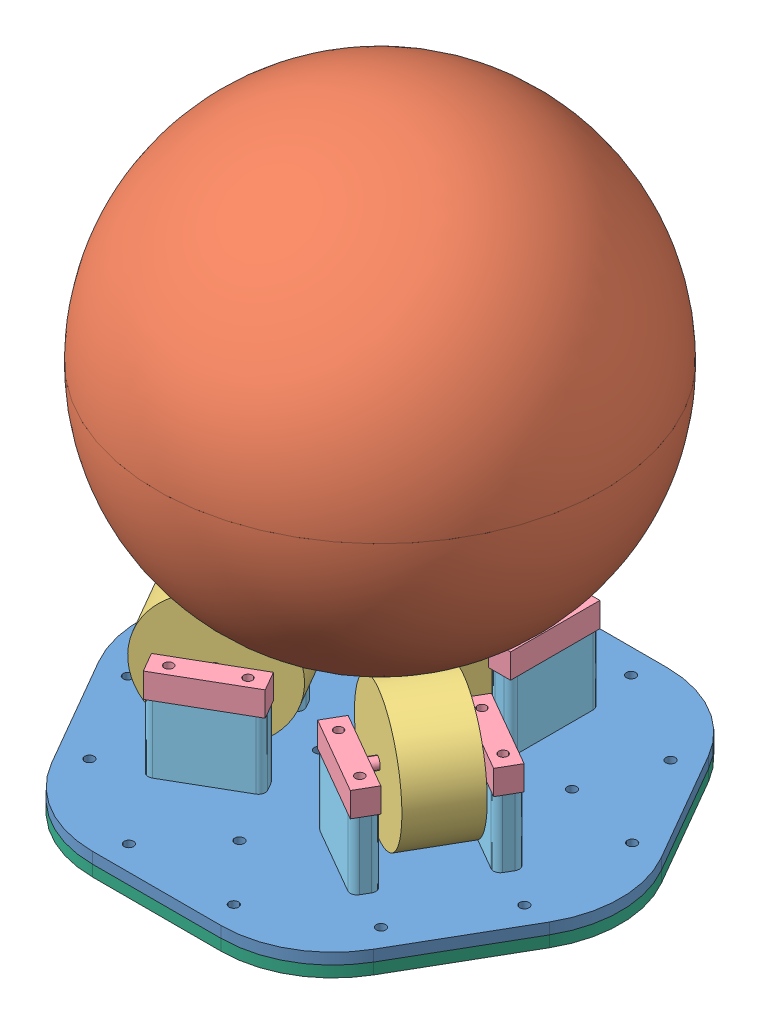
SolidWorks assembly 装配体-底座, configuration 默认. Lengths in mm.
Overall size (280.94 264.42 286.6).
19 component instances, 6 part files, 18 mates.
Components (placement in the parent):
- 底盘-上层-1: 底盘-上层 [默认] at (-27.1025 -44.7578 215.4701) size (215.47 5 200)
- 半球壳-直径200-1: 半球壳-直径200 [默认] at (-27.1025 114.6582 215.4701) x (0.999231 0 -0.039211) z (0.039211 0 0.999231) size (200 100 200)
- 装配体-支撑腿-1: 装配体-支撑腿 [默认] at (-21.0773 -11.8387 210.7731) x (0.072827 0.996458 -0.042047) z (-0.862958 0.084094 0.498229) size (66.06 57 58)
  - 全向轮-1: 全向轮 [默认] at (2.7132 -15.0551 58) size (58 28 58)
  - 全向轮固定架-1: 全向轮固定架 [默认] at (-12.0465 27.4449 36.6833) x (0 -1 0) z (-0.084094 0 0.996458) size (57 11 40)
  - 万向轮支撑腿-分体式-1: 万向轮支撑腿-分体式 [默认] at (-30.9792 17.4449 35.0855) x (0 -1 0) z (-0.084094 0 0.996458) size (10 30 40)
  - 万向轮支撑腿-分体式-2: 万向轮支撑腿-分体式 [默认] at (-30.9792 -29.5551 35.0855) x (0 -1 0) z (-0.084094 0 0.996458) size (10 30 40)
- 装配体-支撑腿-2: 装配体-支撑腿 [默认] at (-34.1827 -11.8387 212.6006) x (-0.072827 0.996458 -0.042047) z (0.862958 0.084094 0.498229) size (66.06 57 58)
  - 全向轮-1: 全向轮 [默认] at (2.7132 -15.0551 58) size (58 28 58)
  - 全向轮固定架-1: 全向轮固定架 [默认] at (-12.0465 27.4449 36.6833) x (0 -1 0) z (-0.084094 0 0.996458) size (57 11 40)
  - 万向轮支撑腿-分体式-1: 万向轮支撑腿-分体式 [默认] at (-30.9792 17.4449 35.0855) x (0 -1 0) z (-0.084094 0 0.996458) size (10 30 40)
  - 万向轮支撑腿-分体式-2: 万向轮支撑腿-分体式 [默认] at (-30.9792 -29.5551 35.0855) x (0 -1 0) z (-0.084094 0 0.996458) size (10 30 40)
- 装配体-支撑腿-3: 装配体-支撑腿 [默认] at (-28.1576 -11.8387 107.9037) x (0 0.996458 -0.084094) z (0 0.084094 0.996458) size (66.06 57 58)
  - 全向轮-1: 全向轮 [默认] at (2.7132 -15.0551 58) size (58 28 58)
  - 全向轮固定架-1: 全向轮固定架 [默认] at (-12.0465 27.4449 36.6833) x (0 -1 0) z (-0.084094 0 0.996458) size (57 11 40)
  - 万向轮支撑腿-分体式-1: 万向轮支撑腿-分体式 [默认] at (-30.9792 17.4449 35.0855) x (0 -1 0) z (-0.084094 0 0.996458) size (10 30 40)
  - 万向轮支撑腿-分体式-2: 万向轮支撑腿-分体式 [默认] at (-30.9792 -29.5551 35.0855) x (0 -1 0) z (-0.084094 0 0.996458) size (10 30 40)
- 底盘-下层-1: 底盘-下层 [默认] at (-27.1025 -49.7578 215.4701) x (-0.5 0 -0.866025) z (0.866025 0 -0.5) size (215.47 5 200)
- 半球壳-直径200-2: 半球壳-直径200 [默认] at (-27.1025 114.6582 215.4701) x (-0.999417 0 0.034133) z (0.034133 0 0.999417) size (200 100 200)
Mates (geometry in assembly coordinates):
- 平行1: parallel aligned: plane of 底盘-1 through (-27.1025 -39.7578 215.4701) normal (0 1 0); plane of 半球壳-直径200-1 through (-27.1025 114.6582 215.4701) normal (0 1 0)
- 重合1: coincident anti-aligned: plane of 底盘-上层-1 through (-27.1025 -39.7578 215.4701) normal (0 1 0); plane of 装配体-支撑腿-1/万向轮支撑腿-分体式-2 through (-38.8332 -39.7578 255.1518) normal (0 -1 0)
- 重合2: coincident anti-aligned: plane of 底盘-上层-1 through (-27.1025 -39.7578 215.4701) normal (0 1 0); plane of 装配体-支撑腿-2/万向轮支撑腿-分体式-1 through (-10.3717 -39.7578 246.4915) normal (0 -1 0)
- 重合3: coincident anti-aligned: plane of 底盘-上层-1 through (-27.1025 -39.7578 215.4701) normal (0 1 0); plane of 装配体-支撑腿-3/万向轮支撑腿-分体式-2 through (1.3975 -39.7578 145.4701) normal (0 -1 0)
- 同心4: concentric anti-aligned: cylinder of 底盘-上层-1 through (-50.6025 -44.7578 152.4701) axis (0 1 0) radius 2.1; cylinder of 装配体-支撑腿-3/全向轮固定架-1 through (-50.6025 1.2422 152.4701) axis (0 -1 0) radius 2
- 同心5: concentric anti-aligned: cylinder of 底盘-上层-1 through (-3.6025 -44.7578 152.4701) axis (0 1 0) radius 2.1; cylinder of 装配体-支撑腿-3/全向轮固定架-1 through (-3.6025 1.2422 152.4701) axis (0 -1 0) radius 2
- 同心6: concentric anti-aligned: cylinder of 底盘-上层-1 through (-93.4121 -44.7578 226.6185) axis (0 1 0) radius 2.1; cylinder of 装配体-支撑腿-1/全向轮固定架-1 through (-93.4121 1.2422 226.6185) axis (0 -1 0) radius 2
- 同心8: concentric anti-aligned: cylinder of 底盘-上层-1 through (-69.9121 -44.7578 267.3217) axis (0 1 0) radius 2.1; cylinder of 装配体-支撑腿-1/全向轮固定架-1 through (-69.9121 1.2422 267.3217) axis (0 -1 0) radius 2
- 同心9: concentric anti-aligned: cylinder of 底盘-上层-1 through (15.7071 -44.7578 267.3217) axis (0 1 0) radius 2.1; cylinder of 装配体-支撑腿-2/全向轮固定架-1 through (15.7071 1.2422 267.3217) axis (0 -1 0) radius 2
- 同心10: concentric anti-aligned: cylinder of 底盘-上层-1 through (39.2071 -44.7578 226.6185) axis (0 1 0) radius 2.1; cylinder of 装配体-支撑腿-2/全向轮固定架-1 through (39.2071 1.2422 226.6185) axis (0 -1 0) radius 2
- 相切1: tangent anti-aligned: sphere of 半球壳-直径200-1; cylinder of 装配体-支撑腿-3/全向轮-1 through (-41.1025 -4.2578 165.4701) axis (1 0 0) radius 29
- 相切2: tangent anti-aligned: sphere of 半球壳-直径200-1; cylinder of 装配体-支撑腿-1/全向轮-1 through (-77.4037 -4.2578 228.3457) axis (0.5 0 0.866025) radius 29
- 相切4: tangent anti-aligned: sphere of 半球壳-直径200-1; cylinder of 装配体-支撑腿-2/全向轮-1 through (9.1988 -4.2578 252.5944) axis (0.5 0 -0.866025) radius 29
- 重合4: coincident anti-aligned: plane of 底盘-上层-1 through (-27.1025 -44.7578 215.4701) normal (0 -1 0); plane of 底盘-下层-1 through (-27.1025 -44.7578 215.4701) normal (0 1 0)
- 同心14: concentric aligned: cylinder of 底盘-上层-1 through (38.2238 -44.7578 280.3217) axis (0 1 0) radius 2.1; cylinder of 底盘-下层-1 through (38.2238 -49.7578 280.3217) axis (0 1 0) radius 4
- 同心15: concentric aligned: cylinder of 底盘-上层-1 through (61.7238 -44.7578 239.6185) axis (0 1 0) radius 2.1; cylinder of 底盘-下层-1 through (61.7238 -49.7578 239.6185) axis (0 1 0) radius 4
- 重合5: coincident: circle of 半球壳-直径200-1; sphere of 半球壳-直径200-2
- 重合6: coincident anti-aligned: plane of 半球壳-直径200-1 through (-27.1025 114.6582 215.4701) normal (0 1 0); plane of 半球壳-直径200-2 through (-27.1025 114.6582 215.4701) normal (0 -1 0)
